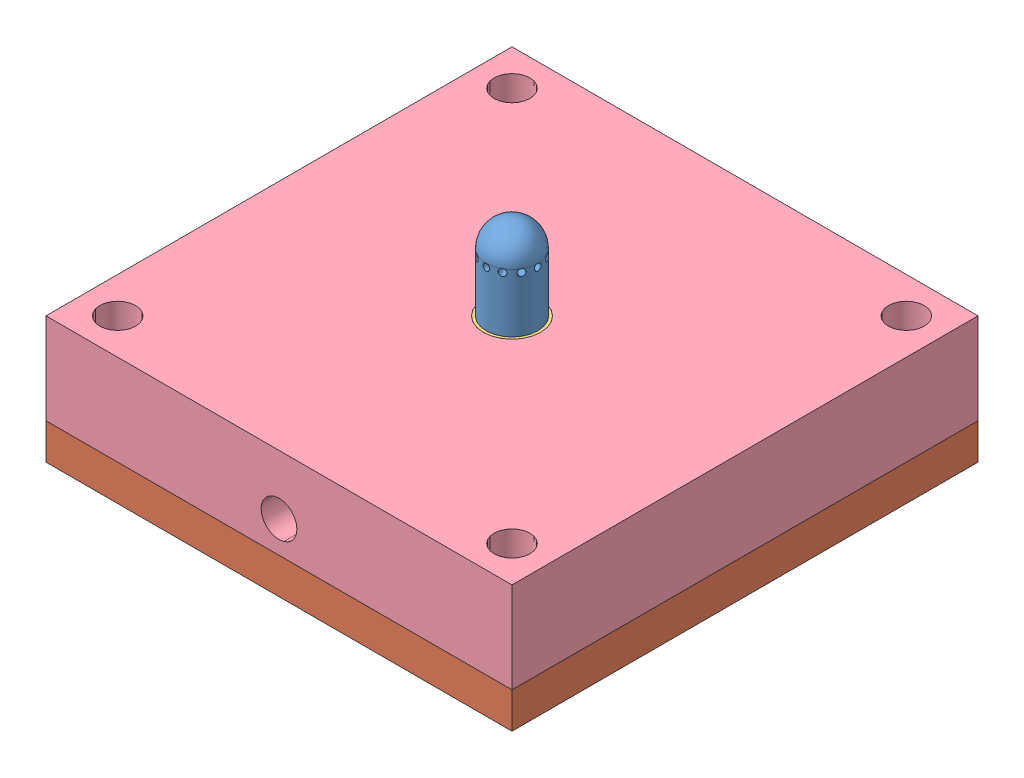
SolidWorks assembly Assembly_V2_Cold_Test, configuration Default. Lengths in mm.
Overall size (82.55 56.44 82.55).
4 component instances, 4 part files, 16 mates.
Components (placement in the parent):
- Part_Pintle_V2.1-1: Part_Pintle_V2.1 [Default] at (-41.275 23.0788 41.275) x (0 0 1) z (1 0 0) size (35.56 56.44 35.56)
- Part_Cold_Test_Plate_V1-1: Part_Cold_Test_Plate_V1 [Default] at (-41.275 0 41.275) x (0 0 1) z (1 0 0) size (82.55 6.35 82.55)
- V2.0_Annulus_flow_area-1: V2.0_Annulus_flow_area [Default] at (-41.2299 0 20.32) x (0 0 1) z (-1 0 0) size (57.15 16.1 21.97)
- Part_V2_Cold_Test_Annulus-2: Part_V2_Cold_Test_Annulus [Default] at (-41.275 8.7071 41.275) x (0 0 1) z (-1 0 0) size (82.55 16.1 82.55)
Mates (geometry in assembly coordinates):
- Concentric1: concentric: cylinder of ? through (0 101.6046 0) axis (0 -1 0) radius 5.2705; cylinder of Part_Pintle_V2.1-1 through (0 4.7031 0) axis (0 -1 0) radius 4.5847
- Concentric2: concentric: cylinder of Part_Pintle_V2.1-1 through (-41.275 14.8631 41.275) axis (0 -1 0) radius 4.5847; circle of Part_Cold_Test_Plate_V1-1
- Concentric3: concentric: cylinder of ? through (26.255 -6.985 -9.556) axis (0 -1 0) radius 1.0325; cylinder of Part_Cold_Test_Plate_V1-1 through (26.255 -10.159 -9.556) axis (0 -1 0) radius 1.632
- Coincident4: coincident: plane of Part_Pintle_V2.1-1 through (-41.275 -6.35 41.275) normal (0 1 0); plane of Part_Cold_Test_Plate_V1-1 through (-41.275 -6.35 41.275) normal (0 -1 0)
- Coincident5: coincident: plane of ? through (22.6695 -10.16 0) normal (0 -1 0); plane of Part_Cold_Test_Plate_V1-1 through (0 -10.16 0) normal (0 1 0)
- Concentric4: concentric: circle of Part_Pintle_V2.1-1; circle of Part_Cold_Test_Plate_V1-1
- Coincident6: coincident: plane of Part_Cold_Test_Plate_V1-1 through (-41.275 0 41.275) normal (0 1 0); plane of V2.0_Annulus_flow_area-1 through (-41.2299 0 20.32) normal (0 -1 0)
- Distance2: distance = 5.08 mm: plane of Part_Cold_Test_Plate_V1-1 through (0 -6.35 82.55) normal (0 0 1); plane of V2.0_Annulus_flow_area-1 through (-20.9099 16.0985 77.47) normal (0 0 1)
- Coincident12: coincident: point of Part_Cold_Test_Plate_V1-1; point of assembly
- Coincident13: coincident: line of Part_Cold_Test_Plate_V1-1 through (-82.55 0 0) axis (1 0 0); line of assembly
- Coincident14: coincident: line of Part_Cold_Test_Plate_V1-1 through (0 0 0) axis (0 0 1); line of assembly
- Concentric5: concentric: cylinder of Part_Pintle_V2.1-1 through (-41.275 14.8631 41.275) axis (0 -1 0) radius 4.5847; cylinder of Part_V2_Cold_Test_Annulus-2 through (-41.275 110.3118 41.275) axis (0 -1 0) radius 5.08
- Concentric8: concentric: cylinder of Part_Cold_Test_Plate_V1-1 through (-17.0783 0.001 55.245) axis (0 -1 0) radius 1.632; cylinder of Part_V2_Cold_Test_Annulus-2 through (-17.0783 3.175 55.245) axis (0 -1 0) radius 1.0325
- Coincident15: coincident: plane of Part_Cold_Test_Plate_V1-1 through (-41.275 0 41.275) normal (0 1 0); plane of Part_V2_Cold_Test_Annulus-2 through (-41.275 0 63.9445) normal (0 -1 0)
- Coincident16: coincident: plane of Part_V2_Cold_Test_Annulus-2 through (-41.275 16.0985 46.5455) normal (0 1 0); plane of ? through (-41.275 16.0985 41.275) normal (0 -1 0)
- Concentric9: concentric: cylinder of Part_Pintle_V2.1-1 through (-41.275 14.8631 41.275) axis (0 -1 0) radius 4.5847; cylinder of ? through (-41.275 143.0985 41.275) axis (0 -1 0) radius 38.1
